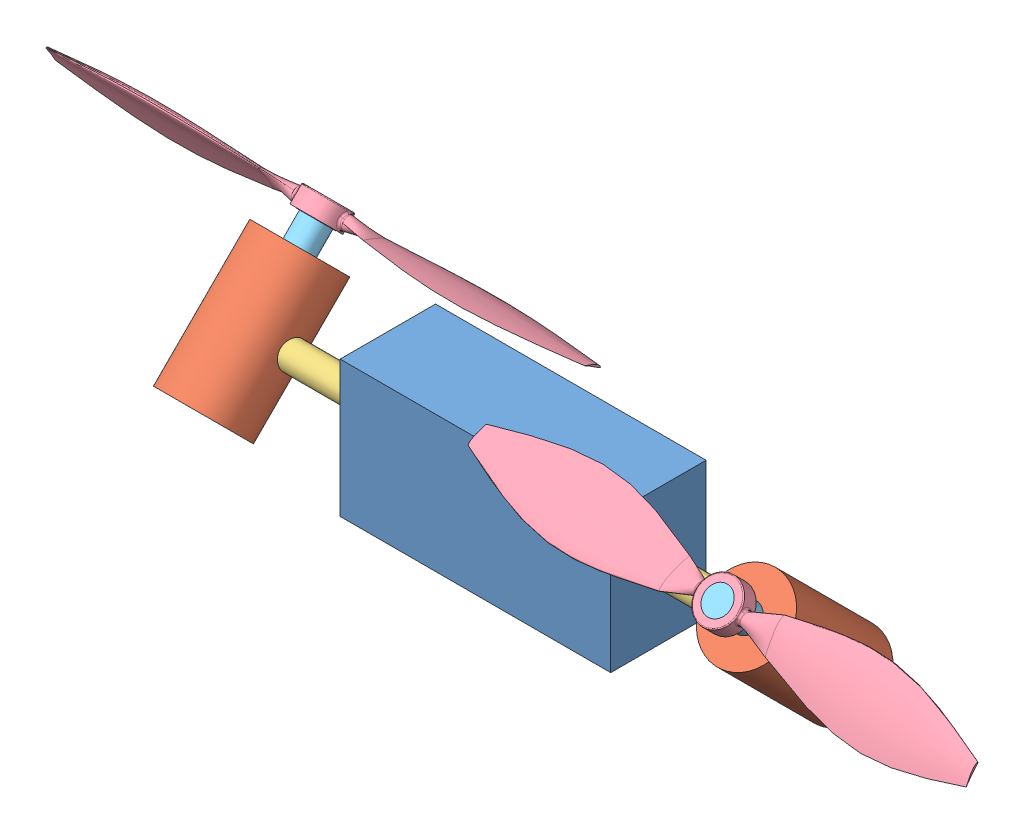
SolidWorks assembly Concept2, configuration Default. Lengths in mm.
Overall size (401.61 150.09 200.15).
9 component instances, 5 part files, 10 mates.
Components (placement in the parent):
- Middle-1: Middle [Default] at origin size (99.27 50 35)
- Motor Housing-1: Motor Housing [Default] at (99.635 7.3223 -17.6777) x (1 0 0) z (0 -0.707107 0.707107) size (30 50 30)
- Motor Housing-2: Motor Housing [Default] at (-99.635 7.3223 17.6777) x (-1 0 0) z (0 -0.707107 -0.707107) size (30 50 30)
- Shaft-1: Shaft [Default] at (-39.635 25 0) x (0 -0.838026 -0.54563) z (0 0.54563 -0.838026) size (10 55 10)
- Shaft-2: Shaft [Default] at (94.635 25 0) x (0 1 0) z (0 0 1) size (10 55 10)
- User Library-7_5 inch prop (1)-1: User Library-7_5 inch prop (1) [Default] at (-99.635 51.0392 -26.0392) x (-0.068561 -0.705443 -0.705443) z (0 -0.707107 0.707107) size (190.5 190.53 9.14)
- PropShaft-1: PropShaft [Default] at (-99.635 35.6066 -10.6066) x (-0.64845 0.53829 0.53829) z (-0.761257 -0.458524 -0.458524) size (10 25 10)
- PropShaft-2: PropShaft [Default] at (99.635 35.6066 10.6066) x (1 0 0) z (0 -0.707107 0.707107) size (10 25 10)
- User Library-7_5 inch prop (1)-2: User Library-7_5 inch prop (1) [Default] at (99.635 51.0392 26.0392) x (0.05955 0.705852 -0.705852) z (0 -0.707107 -0.707107) size (190.5 190.53 9.14)
Mates (geometry in assembly coordinates):
- Coincident7: coincident anti-aligned: circle of Motor Housing-2; circle of Shaft-1
- Coincident8: coincident aligned: circle of Middle-1; circle of Shaft-1
- Coincident9: coincident anti-aligned: circle of Middle-1; circle of Shaft-2
- Coincident10: coincident aligned: circle of Motor Housing-1; circle of Shaft-2
- Coincident11: coincident aligned: circle of Motor Housing-2; circle of PropShaft-1
- Coincident12: coincident aligned: circle of Motor Housing-1; circle of PropShaft-2
- Coincident13: coincident anti-aligned: circle of User Library-7_5 inch prop (1)-1; circle of PropShaft-1
- Coincident14: coincident anti-aligned: circle of PropShaft-2; circle of User Library-7_5 inch prop (1)-2
- LimitAngle1: limit planar angle = 0.785398 rad aligned: plane of Motor Housing-2 through (-99.635 7.3223 17.6777) normal (0 -0.707107 0.707107); plane of Middle-1 through (-49.635 50 17.5) normal (0 0 1)
- LimitAngle2: limit planar angle = 2.356194 rad aligned: plane of Middle-1 through (-49.635 50 17.5) normal (0 0 1); plane of Motor Housing-1 through (99.635 7.3223 -17.6777) normal (0 -0.707107 -0.707107)
